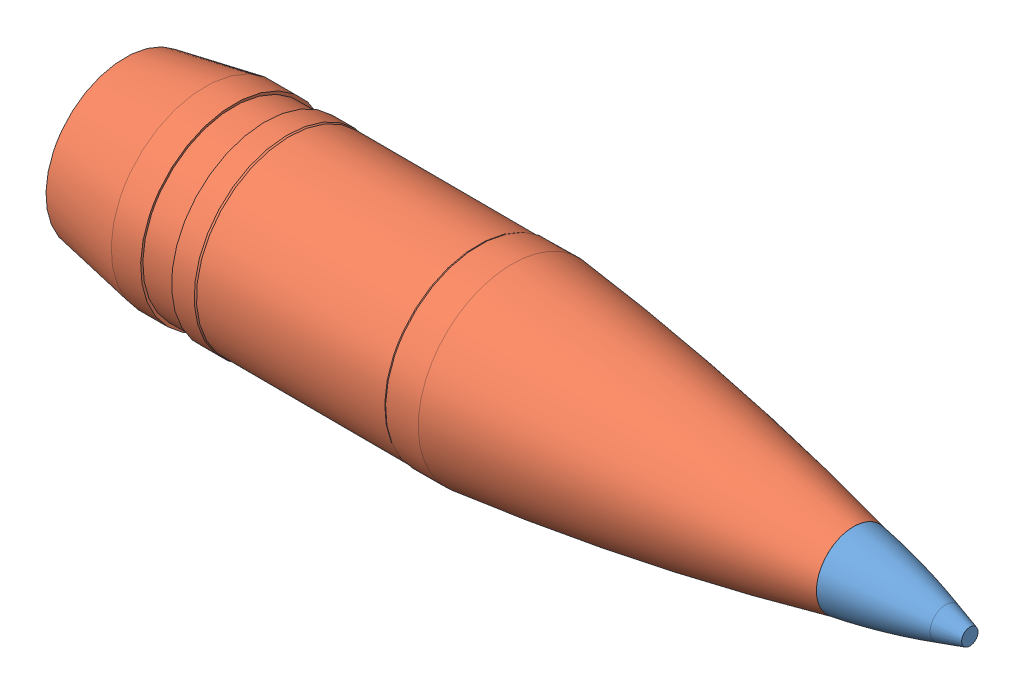
SolidWorks assembly sklop onaj bolji, configuration Default. Lengths in mm.
Overall size (697.55 212.52 212.52).
3 component instances, 3 part files, 4 mates.
Components (placement in the parent):
- upaljac-1: upaljac [Default] at (44.4924 78.2369 96.119) size (136.66 61.26 61.26)
- tijelo projektila-1: tijelo projektila [Default] at (-570.4766 78.2369 96.119) x (0 0.858793 -0.512323) z (0 -0.512323 -0.858793) size (155 601.53 155)
- jedini eks koji valja-1: jedini eks koji valja [Default] at (-570.4766 78.2369 96.119) x (0 -0.728288 -0.685272) z (0 -0.685272 0.728288) size (123.46 521.25 123.46)
Mates (geometry in assembly coordinates):
- Coincident8: coincident aligned: axis of upaljac-1 through (92.1489 78.2369 96.119) axis (-1 0 0); axis of tijelo projektila-1 through (31.0492 78.2369 96.119) axis (-1 0 0)
- Coincident9: coincident anti-aligned: plane of upaljac-1 through (31.0492 101.8569 96.119) normal (-1 0 0); plane of tijelo projektila-1 through (31.0492 96.9534 84.9534) normal (1 0 0)
- Coincident12: coincident aligned: axis of tijelo projektila-1 through (-38.4929 78.2369 96.119) axis (-1 0 0); axis of jedini eks koji valja-1 through (-72.781 78.2369 96.119) axis (-1 0 0)
- Coincident13: coincident anti-aligned: plane of tijelo projektila-1 through (-534.8057 78.2369 96.119) normal (1 0 0); plane of jedini eks koji valja-1 through (-534.8057 63.4973 82.25) normal (-1 0 0)
